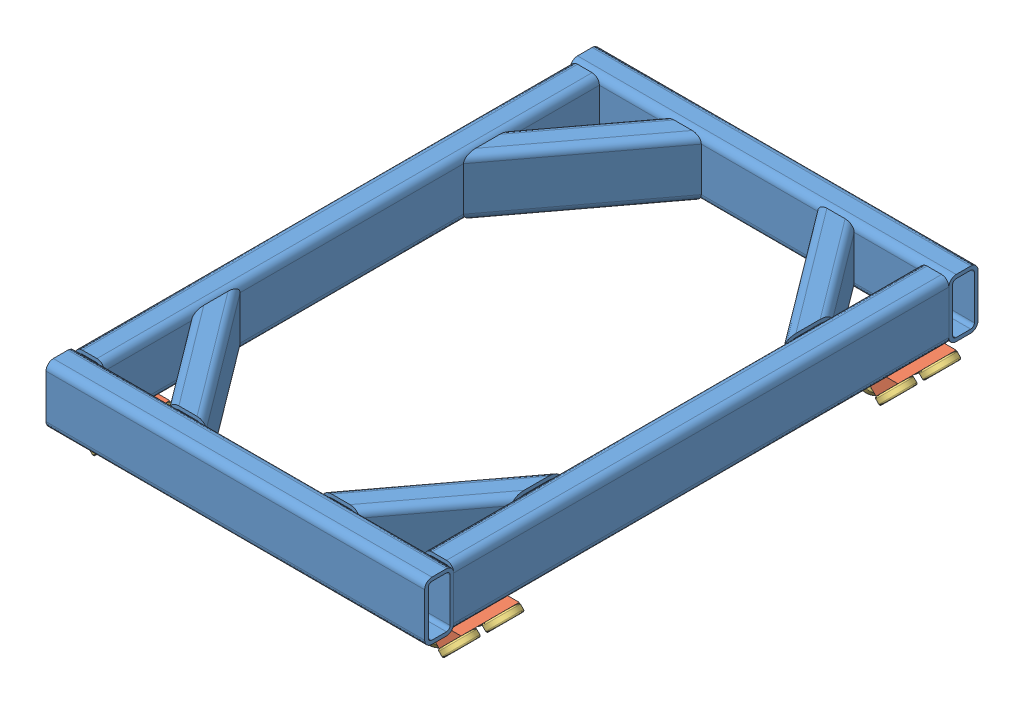
SolidWorks assembly assembled_cart, configuration Default. Lengths in mm.
Overall size (716.87 382.81 1373.57).
25 component instances, 3 part files, 14 mates.
Components (placement in the parent):
- cart_main_body-1: cart_main_body [Default<As Machined>] at (-2.9884 -5.8223 5.5325) size (660.4 326.85 1373.57)
- roller-5: roller [Default] at (-294.3069 -105.5568 399.7216) size (107.27 62.65 151.7)
  - track_hugger-1: track_hugger [Default] at (39.8877 23.5346 -63.9891) size (76.2 38.1 101.6)
  - wheel_bearing-1: wheel_bearing [Default] at (-31.442 28.7951 -44.9391) x (0.400895 -0.400895 0.823751) z (0.58248 -0.58248 -0.566952) size (54 12.7 54)
  - wheel_bearing-2: wheel_bearing [Default] at (13.4593 19.8148 24.9109) x (-0.400895 -0.400895 0.823751) z (-0.58248 -0.58248 -0.566952) size (54 12.7 54)
  - wheel_bearing-3: wheel_bearing [Default] at (-31.442 28.7951 18.5609) x (-0.707106 0.707106 -0.001858) z (-0.001314 0.001314 0.999998) size (54 12.7 54)
  - wheel_bearing-4: wheel_bearing [Default] at (4.479 28.7951 -51.2891) x (-0.551896 -0.551896 -0.625156) z (-0.442052 -0.442052 0.780499) size (54 12.7 54)
- roller-2: roller [Default] at (-294.3069 -105.5568 -362.2784) size (107.27 62.65 151.7)
  - track_hugger-1: track_hugger [Default] at (39.8877 23.5346 -63.9891) size (76.2 38.1 101.6)
  - wheel_bearing-1: wheel_bearing [Default] at (-31.442 28.7951 -44.9391) x (0.400895 -0.400895 0.823751) z (0.58248 -0.58248 -0.566952) size (54 12.7 54)
  - wheel_bearing-2: wheel_bearing [Default] at (13.4593 19.8148 24.9109) x (-0.400895 -0.400895 0.823751) z (-0.58248 -0.58248 -0.566952) size (54 12.7 54)
  - wheel_bearing-3: wheel_bearing [Default] at (-31.442 28.7951 18.5609) x (-0.707106 0.707106 -0.001858) z (-0.001314 0.001314 0.999998) size (54 12.7 54)
  - wheel_bearing-4: wheel_bearing [Default] at (4.479 28.7951 -51.2891) x (-0.551896 -0.551896 -0.625156) z (-0.442052 -0.442052 0.780499) size (54 12.7 54)
- roller-3: roller [Default] at (315.2931 -105.5568 399.7216) size (107.27 62.65 151.7)
  - track_hugger-1: track_hugger [Default] at (39.8877 23.5346 -63.9891) size (76.2 38.1 101.6)
  - wheel_bearing-1: wheel_bearing [Default] at (-31.442 28.7951 -44.9391) x (0.400895 -0.400895 0.823751) z (0.58248 -0.58248 -0.566952) size (54 12.7 54)
  - wheel_bearing-2: wheel_bearing [Default] at (13.4593 19.8148 24.9109) x (-0.400895 -0.400895 0.823751) z (-0.58248 -0.58248 -0.566952) size (54 12.7 54)
  - wheel_bearing-3: wheel_bearing [Default] at (-31.442 28.7951 18.5609) x (-0.707106 0.707106 -0.001858) z (-0.001314 0.001314 0.999998) size (54 12.7 54)
  - wheel_bearing-4: wheel_bearing [Default] at (4.479 28.7951 -51.2891) x (-0.551896 -0.551896 -0.625156) z (-0.442052 -0.442052 0.780499) size (54 12.7 54)
- roller-4: roller [Default] at (315.2931 -105.5568 -362.2784) size (107.27 62.65 151.7)
  - track_hugger-1: track_hugger [Default] at (39.8877 23.5346 -63.9891) size (76.2 38.1 101.6)
  - wheel_bearing-1: wheel_bearing [Default] at (-31.442 28.7951 -44.9391) x (0.400895 -0.400895 0.823751) z (0.58248 -0.58248 -0.566952) size (54 12.7 54)
  - wheel_bearing-2: wheel_bearing [Default] at (13.4593 19.8148 24.9109) x (-0.400895 -0.400895 0.823751) z (-0.58248 -0.58248 -0.566952) size (54 12.7 54)
  - wheel_bearing-3: wheel_bearing [Default] at (-31.442 28.7951 18.5609) x (-0.707106 0.707106 -0.001858) z (-0.001314 0.001314 0.999998) size (54 12.7 54)
  - wheel_bearing-4: wheel_bearing [Default] at (4.479 28.7951 -51.2891) x (-0.551896 -0.551896 -0.625156) z (-0.442052 -0.442052 0.780499) size (54 12.7 54)
Mates (geometry in assembly coordinates):
- Coincident1: coincident anti-aligned: plane of cart_main_body-1 through (-295.0884 -56.6223 -451.6675) normal (0 -1 0); plane of roller-5/track_hugger-1 through (-345.8884 -56.6223 437.3325) normal (0 1 0)
- Coincident2: coincident aligned: plane of cart_main_body-1 through (-307.7884 32.2777 437.3325) normal (0 0 1); plane of roller-5/track_hugger-1 through (-254.4192 -82.0223 437.3325) normal (0 0 1)
- Width2: width aligned: plane of cart_main_body-1 through (-282.3884 -43.9223 -451.6675) normal (1 0 0); plane of cart_main_body-1 through (-333.1884 32.2777 -451.6675) normal (-1 0 0); plane of roller-5/track_hugger-1 through (-307.7884 -94.7223 437.3325) normal (0.707107 -0.707107 0); plane of roller-5/track_hugger-1 through (-345.8884 -56.6223 437.3325) normal (-0.707107 -0.707107 0)
- Width3: width anti-aligned: plane of cart_main_body-1 through (276.4116 32.2777 -451.6675) normal (-1 0 0); plane of cart_main_body-1 through (327.2116 -43.9223 -451.6675) normal (1 0 0); plane of roller-3/track_hugger-1 through (301.8116 -94.7223 437.3325) normal (0.707107 -0.707107 0); plane of roller-3/track_hugger-1 through (263.7116 -56.6223 437.3325) normal (-0.707107 -0.707107 0)
- Width4: width anti-aligned: plane of cart_main_body-1 through (276.4116 32.2777 -451.6675) normal (-1 0 0); plane of cart_main_body-1 through (327.2116 -43.9223 -451.6675) normal (1 0 0); plane of roller-4/track_hugger-1 through (301.8116 -94.7223 -324.6675) normal (0.707107 -0.707107 0); plane of roller-4/track_hugger-1 through (263.7116 -56.6223 -324.6675) normal (-0.707107 -0.707107 0)
- Coincident3: coincident: plane of cart_main_body-1 through (301.8116 -43.9223 -426.2675) normal (0 0 -1); plane of roller-2/track_hugger-1 through (-254.4192 -82.0223 -426.2675) normal (0 0 -1)
- Coincident4: coincident: plane of cart_main_body-1 through (-295.0884 -56.6223 -451.6675) normal (0 -1 0); plane of roller-2/track_hugger-1 through (-345.8884 -56.6223 -324.6675) normal (0 1 0)
- Coincident5: coincident aligned: plane of cart_main_body-1 through (-307.7884 32.2777 437.3325) normal (0 0 1); plane of roller-3/track_hugger-1 through (355.1808 -82.0223 437.3325) normal (0 0 1)
- Coincident6: coincident anti-aligned: plane of cart_main_body-1 through (314.5116 -56.6223 -451.6675) normal (0 -1 0); plane of roller-3/track_hugger-1 through (263.7116 -56.6223 437.3325) normal (0 1 0)
- Coincident8: coincident anti-aligned: plane of cart_main_body-1 through (314.5116 -56.6223 -451.6675) normal (0 -1 0); plane of roller-4/track_hugger-1 through (263.7116 -56.6223 -324.6675) normal (0 1 0)
- Coincident9: coincident aligned: plane of cart_main_body-1 through (301.8116 -43.9223 -426.2675) normal (0 0 -1); plane of roller-4/track_hugger-1 through (355.1808 -82.0223 -426.2675) normal (0 0 -1)
- Width5: width anti-aligned: plane of cart_main_body-1 through (-333.1884 32.2777 -451.6675) normal (-1 0 0); plane of cart_main_body-1 through (-282.3884 -43.9223 -451.6675) normal (1 0 0); plane of roller-2/track_hugger-1 through (-307.7884 -94.7223 -324.6675) normal (0.707107 -0.707107 0); plane of roller-2/track_hugger-1 through (-345.8884 -56.6223 -324.6675) normal (-0.707107 -0.707107 0)
- Width6: width anti-aligned: plane of cart_main_body-1 through (-282.3884 -43.9223 -451.6675) normal (1 0 0); plane of cart_main_body-1 through (-333.1884 32.2777 -451.6675) normal (-1 0 0); plane of roller-5/track_hugger-1 through (-345.8884 -56.6223 437.3325) normal (-0.707107 -0.707107 0); plane of roller-5/track_hugger-1 through (-307.7884 -94.7223 437.3325) normal (0.707107 -0.707107 0)
- Width7: width anti-aligned: plane of cart_main_body-1 through (276.4116 32.2777 -451.6675) normal (-1 0 0); plane of cart_main_body-1 through (327.2116 -43.9223 -451.6675) normal (1 0 0); plane of roller-4/track_hugger-1 through (301.8116 -94.7223 -324.6675) normal (0.707107 -0.707107 0); plane of roller-4/track_hugger-1 through (263.7116 -56.6223 -324.6675) normal (-0.707107 -0.707107 0)
